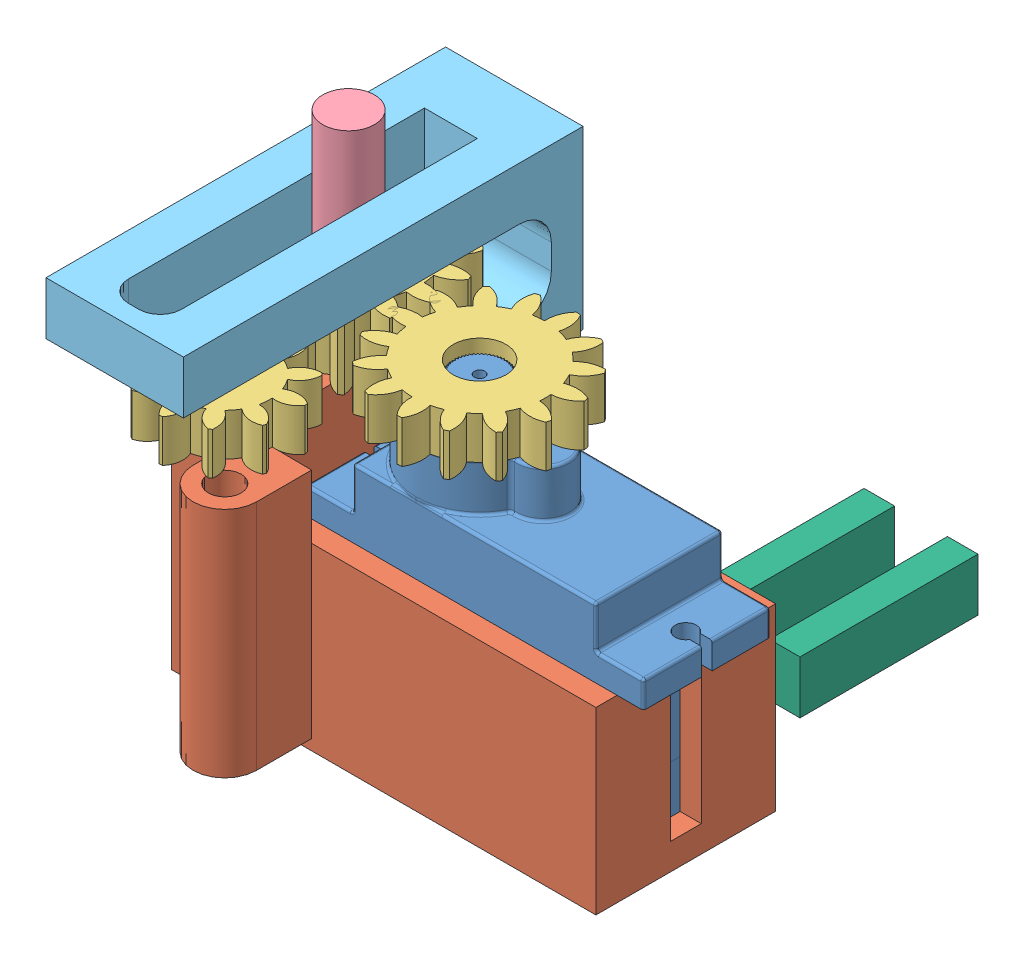
SolidWorks assembly onewaymechanism, configuration Default. Lengths in mm.
Overall size (47.98 45.61 57.37).
8 component instances, 6 part files, 15 mates.
Components (placement in the parent):
- servo motor assembly-1: servo motor assembly [Default] at (0.9929 9.6118 28.8258) size (32 28.96 12.1)
- servo_holder-1: servo_holder [Default] at (0.9929 2.6118 28.3258) size (40.17 26 25.21)
- spur gear_am-1: spur gear_am [Metric - Spur gear 1M 15T 20PA 4FW ---S15N75H50L5N] at (-4.5071 30.6118 28.8258) x (0 1 0) z (-0.866986 0 0.498333) size (4 16.86 16.95)
- spur gear_am-2: spur gear_am [Metric - Spur gear 1M 16T 20PA 6FW ---S16N75H50L5N] at (-20.1749 34.6118 25.5537) x (0 -1 0) z (-0.967925 0 -0.251241) size (6 17.74 17.74)
- spur gear_am-3: spur gear_am [Metric - Spur gear 1M 11T 20PA 4FW ---S11N75H50L3N] at (-15.4051 34.6118 42.0351) x (0 -1 0) z (-0.077042 0 0.997028) size (4 12.78 12.91)
- Part1^onewaymechanism-1: Part1^onewaymechanism [Default] at (-20.1749 25.6118 25.5537) x (0.996412 0 -0.08463) z (0.08463 0 0.996412) size (4.9 20 4.9) (virtual)
- Part2^onewaymechanism-1: Part2^onewaymechanism [Default] at (-23.0015 34.6118 44.3098) size (13 26.62 37.8) (virtual)
- Part3^onewaymechanism-1: Part3^onewaymechanism [Default] at origin size (10.78 5 16.84) (virtual)
Mates (geometry in assembly coordinates):
- Coincident1: coincident anti-aligned: plane of servo motor assembly-1 through (0.9929 19.6118 34.8258) normal (0 0 1); plane of servo_holder-1 through (-10.5071 19.6118 34.8258) normal (0 0 -1)
- Coincident2: coincident anti-aligned: plane of servo motor assembly-1 through (-10.5071 19.6118 28.8258) normal (-1 0 0); plane of servo_holder-1 through (-10.5071 19.6118 21.8258) normal (1 0 0)
- Coincident3: coincident anti-aligned: plane of servo motor assembly-1 through (0.9929 19.6118 28.8258) normal (0 -1 0); plane of servo_holder-1 through (0.9929 19.6118 28.3258) normal (0 1 0)
- Coincident4: coincident anti-aligned: circle of servo motor assembly-1; plane of spur gear_am-1 through (-4.5071 30.6118 28.8258) normal (0 -1 0)
- Concentric1: concentric anti-aligned: cylinder of servo motor assembly-1 through (-4.5071 21.4908 28.8258) axis (0 1 0) radius 2.5; cylinder of spur gear_am-1 through (-4.5071 80.6119 28.8258) axis (0 -1 0) radius 2.5
- Coincident6: coincident aligned: plane of spur gear_am-1 through (-4.5071 34.6118 28.8258) normal (0 1 0); plane of spur gear_am-2 through (-20.1749 34.6118 25.5537) normal (0 1 0)
- Coincident7: coincident aligned: plane of spur gear_am-2 through (-20.1749 34.6118 25.5537) normal (0 1 0); plane of spur gear_am-3 through (-15.4051 34.6118 42.0351) normal (0 1 0)
- Tangent1: tangent anti-aligned: plane of servo_holder-1 through (-17.6749 31.6118 17.7118) normal (-1 0 0); cylinder of spur gear_am-2 through (-20.1749 -15.3882 25.5537) axis (0 1 0) radius 2.5
- Concentric2: concentric aligned: cylinder of servo_holder-1 through (-15.4051 3.6118 42.0351) axis (0 1 0) radius 3; cylinder of spur gear_am-3 through (-15.4051 -15.3882 42.0351) axis (0 1 0) radius 1.5
- Concentric3: concentric anti-aligned: cylinder of spur gear_am-2 through (-20.1749 -15.3882 25.5537) axis (0 1 0) radius 2.5; cylinder of Part1^onewaymechanism-1 through (-20.1749 45.6118 25.5537) axis (0 -1 0) radius 2.45
- Coincident9: coincident anti-aligned: plane of servo_holder-1 through (-15.4051 25.6118 42.0351) normal (0 1 0); plane of Part1^onewaymechanism-1 through (-20.1749 25.6118 25.5537) normal (0 -1 0)
- Coincident12: coincident anti-aligned: plane of spur gear_am-2 through (-20.1749 34.6118 25.5537) normal (0 1 0); plane of Part2^onewaymechanism-1 through (-23.0015 34.6118 44.3098) normal (0 -1 0)
- Tangent2: tangent anti-aligned: cylinder of Part1^onewaymechanism-1 through (-20.1749 45.6118 25.5537) axis (0 -1 0) radius 2.45; plane of Part2^onewaymechanism-1 through (-17.7249 39.6118 15.8258) normal (-1 0 0)
- Parallel2: parallel aligned: plane of servo_holder-1 through (-25.6752 28.6118 19.8258) normal (-1 0 0); plane of Part2^onewaymechanism-1 through (-26.7249 39.6118 12.8258) normal (-1 0 0)
- Coincident14: coincident anti-aligned: plane of servo_holder-1 through (0.9929 4.1118 19.8258) normal (0 0 -1); plane of Part2^onewaymechanism-1 through (-23.0015 34.6118 19.8258) normal (0 0 1)
